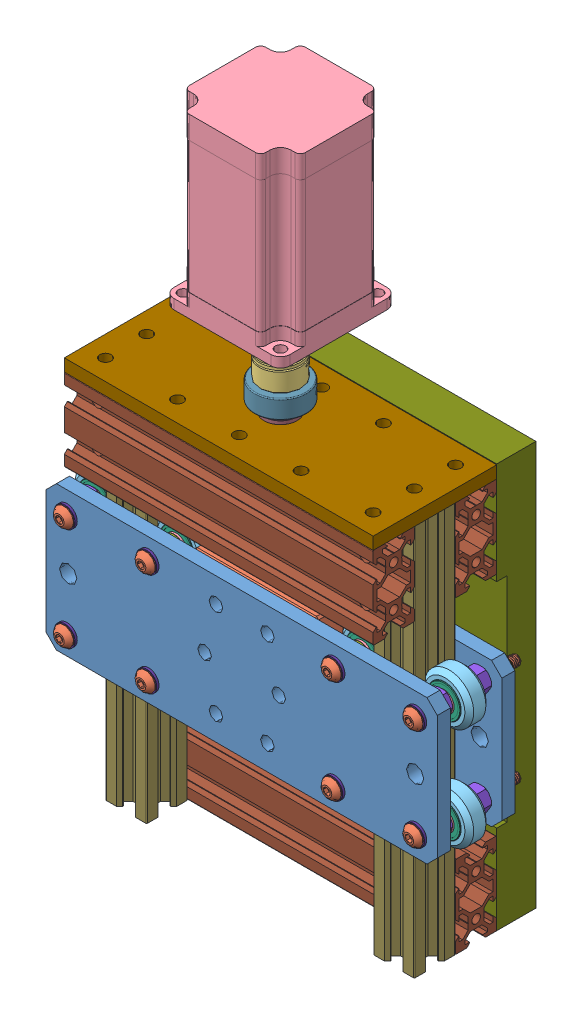
SolidWorks assembly Longitudinal Trim Assembly, configuration Default. Lengths in mm.
Overall size (193.6 327 79.05).
151 component instances, 22 part files, 69 mates.
Components (placement in the parent):
- Trim Sled Assembly-1: Trim Sled Assembly [Default] at origin size (193.6 74.69 37.7)
  - Trim Sled Plate-1: Trim Sled Plate [Default] at origin size (190 70 6.35)
  - Lead Screw Nut Assembly-1: Lead Screw Nut Assembly [Default] at origin size (60 70 25)
    - Lead Screw Nut Clamshell-1: Lead Screw Nut Clamshell [Default] at origin size (60 70 12.5)
    - MISUMI Brass Lead Screw Flange Nut - MTSGR12-1: MISUMI Brass Lead Screw Flange Nut - MTSGR12 [Default] at (0 -15 30) x (0 1 0) z (0 0 1) size (30 44 24)
    - Lead Screw Nut Clamshell-2: Lead Screw Nut Clamshell [Default] at (0 0 60) x (-1 0 0) z (0 0 -1) size (60 70 12.5)
  - Inboard Wheel Stack-1: Inboard Wheel Stack [Default] at (-45.15 -25 23.5) size (23.9 23.9 25)
    - Xtreme Solid V Wheel Kit Assembly-1: Xtreme Solid V Wheel Kit Assembly [Default] at origin size (23.9 23.9 13)
      - Precision Shim - 10x5x1mm-1: Precision Shim - 10x5x1mm [Default] at origin size (10 10 1)
      - Xtreme Solid V Wheel Assembly-1: Xtreme Solid V Wheel Assembly [Default] at (45.15 25 -23.5) size (23.9 23.9 11)
        - Xtreme Solid V Wheel-1: Xtreme Solid V Wheel [Default] at (-45.15 -25 30) x (0 0 1) z (-1 0 0) size (10.2 23.9 23.9)
        - Wheel+Kit+-+5x16x5mm+Sealed+Radial+Ball+Bearing.step.f3d-1: Wheel+Kit+-+5x16x5mm+Sealed+Radial+Ball+Bearing.step.f3d [Default] at (-45.15 -25 30) x (0 1 0) z (-1 0 0) size (16 5 16)
        - Wheel+Kit+-+5x16x5mm+Sealed+Radial+Ball+Bearing.step.f3d-2: Wheel+Kit+-+5x16x5mm+Sealed+Radial+Ball+Bearing.step.f3d [Default] at (-45.15 -25 30) x (0 1 0) z (1 0 0) size (16 5 16)
      - Precision Shim - 10x5x1mm-2: Precision Shim - 10x5x1mm [Default] at (0 0 12) size (10 10 1)
    - Aluminum Spacer 6mm-1: Aluminum Spacer 6mm [Default] at (0 0 -6) size (10 10 6)
    - Aluminum Spacer 6mm-2: Aluminum Spacer 6mm [Default] at (0 0 13) size (10 10 6)
  - Inboard Wheel Stack_1-1: Inboard Wheel Stack_1 [Default] at (-45.15 25 23.5) size (23.9 23.9 25)
    - Xtreme Solid V Wheel Kit Assembly_1-1: Xtreme Solid V Wheel Kit Assembly_1 [Default] at origin size (23.9 23.9 13)
      - Precision Shim - 10x5x1mm-1: Precision Shim - 10x5x1mm [Default] at origin size (10 10 1)
      - Xtreme Solid V Wheel Assembly_1-1: Xtreme Solid V Wheel Assembly_1 [Default] at (45.15 55 -23.5) size (23.9 23.9 11)
        - Xtreme Solid V Wheel-1: Xtreme Solid V Wheel [Default] at (-45.15 -55 30) x (0 0 1) z (-1 0 0) size (10.2 23.9 23.9)
        - Wheel+Kit+-+5x16x5mm+Sealed+Radial+Ball+Bearing.step.f3d-1: Wheel+Kit+-+5x16x5mm+Sealed+Radial+Ball+Bearing.step.f3d [Default] at (-45.15 -55 30) x (0 1 0) z (-1 0 0) size (16 5 16)
        - Wheel+Kit+-+5x16x5mm+Sealed+Radial+Ball+Bearing.step.f3d-2: Wheel+Kit+-+5x16x5mm+Sealed+Radial+Ball+Bearing.step.f3d [Default] at (-45.15 -55 30) x (0 1 0) z (1 0 0) size (16 5 16)
      - Precision Shim - 10x5x1mm-2: Precision Shim - 10x5x1mm [Default] at (0 0 12) size (10 10 1)
    - Aluminum Spacer 6mm-1: Aluminum Spacer 6mm [Default] at (0 0 -6) size (10 10 6)
    - Aluminum Spacer 6mm-2: Aluminum Spacer 6mm [Default] at (0 0 13) size (10 10 6)
  - Inboard Wheel Stack_2-1: Inboard Wheel Stack_2 [Default] at (45.15 25 23.5) size (23.9 23.9 25)
    - Xtreme Solid V Wheel Kit Assembly_2-1: Xtreme Solid V Wheel Kit Assembly_2 [Default] at origin size (23.9 23.9 13)
      - Precision Shim - 10x5x1mm-1: Precision Shim - 10x5x1mm [Default] at origin size (10 10 1)
      - Xtreme Solid V Wheel Assembly_2-1: Xtreme Solid V Wheel Assembly_2 [Default] at (154.85 55 -23.5) size (23.9 23.9 11)
        - Xtreme Solid V Wheel-1: Xtreme Solid V Wheel [Default] at (-154.85 -55 30) x (0 0 1) z (-1 0 0) size (10.2 23.9 23.9)
        - Wheel+Kit+-+5x16x5mm+Sealed+Radial+Ball+Bearing.step.f3d-1: Wheel+Kit+-+5x16x5mm+Sealed+Radial+Ball+Bearing.step.f3d [Default] at (-154.85 -55 30) x (0 1 0) z (-1 0 0) size (16 5 16)
        - Wheel+Kit+-+5x16x5mm+Sealed+Radial+Ball+Bearing.step.f3d-2: Wheel+Kit+-+5x16x5mm+Sealed+Radial+Ball+Bearing.step.f3d [Default] at (-154.85 -55 30) x (0 1 0) z (1 0 0) size (16 5 16)
      - Precision Shim - 10x5x1mm-2: Precision Shim - 10x5x1mm [Default] at (0 0 12) size (10 10 1)
    - Aluminum Spacer 6mm-1: Aluminum Spacer 6mm [Default] at (0 0 -6) size (10 10 6)
    - Aluminum Spacer 6mm-2: Aluminum Spacer 6mm [Default] at (0 0 13) size (10 10 6)
  - Inboard Wheel Stack_3-1: Inboard Wheel Stack_3 [Default] at (45.15 -25 23.5) size (23.9 23.9 25)
    - Xtreme Solid V Wheel Kit Assembly_3-1: Xtreme Solid V Wheel Kit Assembly_3 [Default] at origin size (23.9 23.9 13)
      - Precision Shim - 10x5x1mm-1: Precision Shim - 10x5x1mm [Default] at origin size (10 10 1)
      - Xtreme Solid V Wheel Assembly_3-1: Xtreme Solid V Wheel Assembly_3 [Default] at (154.85 25 -23.5) size (23.9 23.9 11)
        - Xtreme Solid V Wheel-1: Xtreme Solid V Wheel [Default] at (-154.85 -25 30) x (0 0 1) z (-1 0 0) size (10.2 23.9 23.9)
        - Wheel+Kit+-+5x16x5mm+Sealed+Radial+Ball+Bearing.step.f3d-1: Wheel+Kit+-+5x16x5mm+Sealed+Radial+Ball+Bearing.step.f3d [Default] at (-154.85 -25 30) x (0 1 0) z (-1 0 0) size (16 5 16)
        - Wheel+Kit+-+5x16x5mm+Sealed+Radial+Ball+Bearing.step.f3d-2: Wheel+Kit+-+5x16x5mm+Sealed+Radial+Ball+Bearing.step.f3d [Default] at (-154.85 -25 30) x (0 1 0) z (1 0 0) size (16 5 16)
      - Precision Shim - 10x5x1mm-2: Precision Shim - 10x5x1mm [Default] at (0 0 12) size (10 10 1)
    - Aluminum Spacer 6mm-1: Aluminum Spacer 6mm [Default] at (0 0 -6) size (10 10 6)
    - Aluminum Spacer 6mm-2: Aluminum Spacer 6mm [Default] at (0 0 13) size (10 10 6)
  - Outboard Wheel Stack-1: Outboard Wheel Stack [Default] at (-84.85 -25.79 23.5) size (23.9 23.9 30)
    - Xtreme Solid V Wheel Kit Assembly_4-1: Xtreme Solid V Wheel Kit Assembly_4 [Default] at origin size (23.9 23.9 13)
      - Precision Shim - 10x5x1mm-1: Precision Shim - 10x5x1mm [Default] at origin size (10 10 1)
      - Xtreme Solid V Wheel Assembly_4-1: Xtreme Solid V Wheel Assembly_4 [Default] at (84.85 25.79 -23.5) size (23.9 23.9 11)
        - Xtreme Solid V Wheel-1: Xtreme Solid V Wheel [Default] at (-84.85 -25.79 30) x (0 0 1) z (-1 0 0) size (10.2 23.9 23.9)
        - Wheel+Kit+-+5x16x5mm+Sealed+Radial+Ball+Bearing.step.f3d-1: Wheel+Kit+-+5x16x5mm+Sealed+Radial+Ball+Bearing.step.f3d [Default] at (-84.85 -25.79 30) x (0 1 0) z (-1 0 0) size (16 5 16)
        - Wheel+Kit+-+5x16x5mm+Sealed+Radial+Ball+Bearing.step.f3d-2: Wheel+Kit+-+5x16x5mm+Sealed+Radial+Ball+Bearing.step.f3d [Default] at (-84.85 -25.79 30) x (0 1 0) z (1 0 0) size (16 5 16)
      - Precision Shim - 10x5x1mm-2: Precision Shim - 10x5x1mm [Default] at (0 0 12) size (10 10 1)
    - Eccentric Spacer 6mm-1: Eccentric Spacer 6mm [Default] at (0 0.79 -6) x (1 0 0) z (0 -1 0) size (11.55 8.5 10)
    - Eccentric Spacer 6mm-2: Eccentric Spacer 6mm [Default] at (0 0.79 19) x (-1 0 0) z (0 -1 0) size (11.55 8.5 10)
  - Outboard Wheel Stack_1-1: Outboard Wheel Stack_1 [Default] at (-84.85 24.21 23.5) size (23.9 23.9 30)
    - Xtreme Solid V Wheel Kit Assembly_5-1: Xtreme Solid V Wheel Kit Assembly_5 [Default] at origin size (23.9 23.9 13)
      - Precision Shim - 10x5x1mm-1: Precision Shim - 10x5x1mm [Default] at origin size (10 10 1)
      - Xtreme Solid V Wheel Assembly_5-1: Xtreme Solid V Wheel Assembly_5 [Default] at (84.85 55.79 -23.5) size (23.9 23.9 11)
        - Xtreme Solid V Wheel-1: Xtreme Solid V Wheel [Default] at (-84.85 -55.79 30) x (0 0 1) z (-1 0 0) size (10.2 23.9 23.9)
        - Wheel+Kit+-+5x16x5mm+Sealed+Radial+Ball+Bearing.step.f3d-1: Wheel+Kit+-+5x16x5mm+Sealed+Radial+Ball+Bearing.step.f3d [Default] at (-84.85 -55.79 30) x (0 1 0) z (-1 0 0) size (16 5 16)
        - Wheel+Kit+-+5x16x5mm+Sealed+Radial+Ball+Bearing.step.f3d-2: Wheel+Kit+-+5x16x5mm+Sealed+Radial+Ball+Bearing.step.f3d [Default] at (-84.85 -55.79 30) x (0 1 0) z (1 0 0) size (16 5 16)
      - Precision Shim - 10x5x1mm-2: Precision Shim - 10x5x1mm [Default] at (0 0 12) size (10 10 1)
    - Eccentric Spacer 6mm-1: Eccentric Spacer 6mm [Default] at (0 0.79 -6) x (1 0 0) z (0 -1 0) size (11.55 8.5 10)
    - Eccentric Spacer 6mm-2: Eccentric Spacer 6mm [Default] at (0 0.79 19) x (-1 0 0) z (0 -1 0) size (11.55 8.5 10)
  - Outboard Wheel Stack_2-1: Outboard Wheel Stack_2 [Default] at (84.85 24.21 23.5) size (23.9 23.9 30)
    - Xtreme Solid V Wheel Kit Assembly_6-1: Xtreme Solid V Wheel Kit Assembly_6 [Default] at origin size (23.9 23.9 13)
      - Precision Shim - 10x5x1mm-1: Precision Shim - 10x5x1mm [Default] at origin size (10 10 1)
      - Xtreme Solid V Wheel Assembly_6-1: Xtreme Solid V Wheel Assembly_6 [Default] at (115.15 55.79 -23.5) size (23.9 23.9 11)
        - Xtreme Solid V Wheel-1: Xtreme Solid V Wheel [Default] at (-115.15 -55.79 30) x (0 0 1) z (-1 0 0) size (10.2 23.9 23.9)
        - Wheel+Kit+-+5x16x5mm+Sealed+Radial+Ball+Bearing.step.f3d-1: Wheel+Kit+-+5x16x5mm+Sealed+Radial+Ball+Bearing.step.f3d [Default] at (-115.15 -55.79 30) x (0 1 0) z (-1 0 0) size (16 5 16)
        - Wheel+Kit+-+5x16x5mm+Sealed+Radial+Ball+Bearing.step.f3d-2: Wheel+Kit+-+5x16x5mm+Sealed+Radial+Ball+Bearing.step.f3d [Default] at (-115.15 -55.79 30) x (0 1 0) z (1 0 0) size (16 5 16)
      - Precision Shim - 10x5x1mm-2: Precision Shim - 10x5x1mm [Default] at (0 0 12) size (10 10 1)
    - Eccentric Spacer 6mm-1: Eccentric Spacer 6mm [Default] at (0 0.79 -6) x (1 0 0) z (0 -1 0) size (11.55 8.5 10)
    - Eccentric Spacer 6mm-2: Eccentric Spacer 6mm [Default] at (0 0.79 19) x (-1 0 0) z (0 -1 0) size (11.55 8.5 10)
  - Outboard Wheel Stack_3-1: Outboard Wheel Stack_3 [Default] at (84.85 -25.79 23.5) size (23.9 23.9 30)
    - Xtreme Solid V Wheel Kit Assembly_7-1: Xtreme Solid V Wheel Kit Assembly_7 [Default] at origin size (23.9 23.9 13)
      - Precision Shim - 10x5x1mm-1: Precision Shim - 10x5x1mm [Default] at origin size (10 10 1)
      - Xtreme Solid V Wheel Assembly_7-1: Xtreme Solid V Wheel Assembly_7 [Default] at (115.15 25.79 -23.5) size (23.9 23.9 11)
        - Xtreme Solid V Wheel-1: Xtreme Solid V Wheel [Default] at (-115.15 -25.79 30) x (0 0 1) z (-1 0 0) size (10.2 23.9 23.9)
        - Wheel+Kit+-+5x16x5mm+Sealed+Radial+Ball+Bearing.step.f3d-1: Wheel+Kit+-+5x16x5mm+Sealed+Radial+Ball+Bearing.step.f3d [Default] at (-115.15 -25.79 30) x (0 1 0) z (-1 0 0) size (16 5 16)
        - Wheel+Kit+-+5x16x5mm+Sealed+Radial+Ball+Bearing.step.f3d-2: Wheel+Kit+-+5x16x5mm+Sealed+Radial+Ball+Bearing.step.f3d [Default] at (-115.15 -25.79 30) x (0 1 0) z (1 0 0) size (16 5 16)
      - Precision Shim - 10x5x1mm-2: Precision Shim - 10x5x1mm [Default] at (0 0 12) size (10 10 1)
    - Eccentric Spacer 6mm-1: Eccentric Spacer 6mm [Default] at (0 0.79 -6) x (1 0 0) z (0 -1 0) size (11.55 8.5 10)
    - Eccentric Spacer 6mm-2: Eccentric Spacer 6mm [Default] at (0 0.79 19) x (-1 0 0) z (0 -1 0) size (11.55 8.5 10)
  - Trim Sled Plate-2: Trim Sled Plate [Default] at (0 0 31.35) size (190 70 6.35)
- Rear Plate Assembly-1: Rear Plate Assembly [Default] at origin size (150 6 60)
  - Rear Plate-1: Rear Plate [Default] at origin size (150 6 60)
  - 6658K734-1: 6658K734 [Default] at (0 98 30) x (1 0 0) z (0 -1 0) size (12.03 12.03 6)
- Aft Frame Assembly-1: Aft Frame Assembly [Default] at origin size (150 190 60)
  - V-Slot 20x40x150 Linear Rail-1: V-Slot 20x40x150 Linear Rail [Default] at (-75 75 10) x (0 0 -1) z (1 0 0) size (20 40 150)
  - V-Slot 20x20x190 Linear Rail Tapped Ends-1: V-Slot 20x20x190 Linear Rail Tapped Ends [Default] at (65 95 30) x (1 0 0) z (0 -1 0) size (20 20 190)
  - V-Slot 20x20x190 Linear Rail Tapped Ends-2: V-Slot 20x20x190 Linear Rail Tapped Ends [Default] at (-65 95 30) x (1 0 0) z (0 -1 0) size (20 20 190)
  - V-Slot 20x40x150 Linear Rail-2: V-Slot 20x40x150 Linear Rail [Default] at (-75 75 50) x (0 0 -1) z (1 0 0) size (20 40 150)
- V-Slot 20x40x150 Linear Rail-1: V-Slot 20x40x150 Linear Rail [Default] at (-75 -75 10) x (0 0 -1) z (1 0 0) size (20 40 150)
- 7806K630-1: 7806K630 [Default] at (0 92.5 30) size (16 5.01 16)
- 7806K630-2: 7806K630 [Default] at (0 103.5 30) size (16 5.01 16)
- 57445K24 - 8mm Clamping Shaft Collar-1: 57445K24 - 8mm Clamping Shaft Collar [Default] at (0 110.5 30) x (1 0 0) z (0 1 0) size (25 25.02 9.05)
- MTSBRA12-160-S35-Q8-1: MTSBRA12-160-S35-Q8 [Default] at (0 125 30) x (1 0 0) z (0 -1 0) size (11.91 11.91 160)
- Trim Riser Board-1: Trim Riser Board [Default] at origin size (150 196.35 19.05)
- 93475A240-1: 93475A240 [Default] at (84.85 -25 48.85) x (0.893587 -0.448891 0) z (0 0 1) size (10 10 1.1)
- 93475A240-2: 93475A240 [Default] at (84.85 -25 10.05) x (0.893587 -0.448891 0) z (0 0 1) size (10 10 1.1)
- 93625A200 - M5 x 0.8 mm Nylon-Insert Locknut-1: 93625A200 - M5 x 0.8 mm Nylon-Insert Locknut [Default] at (84.85 -25 10.05) x (1 0 0) z (0 0 -1) size (8 9.24 5)
  - 93625A200 - M5 x 0.8 mm Nylon-Insert Locknut_2-1: 93625A200 - M5 x 0.8 mm Nylon-Insert Locknut_2 [Default] at origin size (8 9.24 5)
  - 93625A200 - M5 x 0.8 mm Nylon-Insert Locknut-1: 93625A200 - M5 x 0.8 mm Nylon-Insert Locknut [Default] at origin size (7.53 7.53 0.53)
- 92095A228 - BHCS, M5-0.8 X 50, 18-8-1: 92095A228 - BHCS, M5-0.8 X 50, 18-8 [92095A228] at (84.85 -25 52.7) x (-0.790957 0.611872 0) z (0 0 1) size (9.5 9.5 53.02)
- 93475A240-3: 93475A240 [Default] at (45.15 -25 48.85) x (0.953456 -0.301532 0) z (0 0 1) size (10 10 1.1)
- 93475A240-4: 93475A240 [Default] at (45.15 -25 10.05) x (0.953456 -0.301532 0) z (0 0 1) size (10 10 1.1)
- 93625A200 - M5 x 0.8 mm Nylon-Insert Locknut-2: 93625A200 - M5 x 0.8 mm Nylon-Insert Locknut [Default] at (45.15 -25 10.05) x (0.987351 0.158553 0) z (0 0 -1) size (8 9.24 5)
  - 93625A200 - M5 x 0.8 mm Nylon-Insert Locknut_2-1: 93625A200 - M5 x 0.8 mm Nylon-Insert Locknut_2 [Default] at origin size (8 9.24 5)
  - 93625A200 - M5 x 0.8 mm Nylon-Insert Locknut-1: 93625A200 - M5 x 0.8 mm Nylon-Insert Locknut [Default] at origin size (7.53 7.53 0.53)
- 92095A228 - BHCS, M5-0.8 X 50, 18-8-2: 92095A228 - BHCS, M5-0.8 X 50, 18-8 [92095A228] at (45.15 -25 52.7) x (-0.877966 0.478723 0) z (0 0 1) size (9.5 9.5 53.02)
- 93475A240-5: 93475A240 [Default] at (84.85 24.21 48.85) x (0.98409 -0.177672 0) z (0 0 1) size (10 10 1.1)
- 93475A240-6: 93475A240 [Default] at (84.85 24.21 10.05) x (0.98409 -0.177672 0) z (0 0 1) size (10 10 1.1)
- 93625A200 - M5 x 0.8 mm Nylon-Insert Locknut-3: 93625A200 - M5 x 0.8 mm Nylon-Insert Locknut [Default] at (84.85 24.21 10.05) x (0.959125 0.282984 0) z (0 0 -1) size (8 9.24 5)
  - 93625A200 - M5 x 0.8 mm Nylon-Insert Locknut_2-1: 93625A200 - M5 x 0.8 mm Nylon-Insert Locknut_2 [Default] at origin size (8 9.24 5)
  - 93625A200 - M5 x 0.8 mm Nylon-Insert Locknut-1: 93625A200 - M5 x 0.8 mm Nylon-Insert Locknut [Default] at origin size (7.53 7.53 0.53)
- 92095A228 - BHCS, M5-0.8 X 50, 18-8-3: 92095A228 - BHCS, M5-0.8 X 50, 18-8 [92095A228] at (84.85 24.21 52.7) x (-0.931776 0.363033 0) z (0 0 1) size (9.5 9.5 53.02)
- 93475A240-7: 93475A240 [Default] at (45.15 25 48.85) x (0.996366 -0.085169 0) z (0 0 1) size (10 10 1.1)
- 93475A240-8: 93475A240 [Default] at (45.15 25 10.05) x (0.996366 -0.085169 0) z (0 0 1) size (10 10 1.1)
- 93625A200 - M5 x 0.8 mm Nylon-Insert Locknut-4: 93625A200 - M5 x 0.8 mm Nylon-Insert Locknut [Default] at (45.15 25 10.05) x (0.928571 0.371154 0) z (0 0 -1) size (8 9.24 5)
  - 93625A200 - M5 x 0.8 mm Nylon-Insert Locknut_2-1: 93625A200 - M5 x 0.8 mm Nylon-Insert Locknut_2 [Default] at origin size (8 9.24 5)
  - 93625A200 - M5 x 0.8 mm Nylon-Insert Locknut-1: 93625A200 - M5 x 0.8 mm Nylon-Insert Locknut [Default] at origin size (7.53 7.53 0.53)
- 92095A228 - BHCS, M5-0.8 X 50, 18-8-4: 92095A228 - BHCS, M5-0.8 X 50, 18-8 [92095A228] at (45.15 25 52.7) x (-0.961559 0.2746 0) z (0 0 1) size (9.5 9.5 53.02)
- 93475A240-9: 93475A240 [Default] at (-45.15 -25 48.85) x (0.999525 -0.030802 0) z (0 0 1) size (10 10 1.1)
- 93475A240-10: 93475A240 [Default] at (-45.15 -25 10.05) x (0.999525 -0.030802 0) z (0 0 1) size (10 10 1.1)
- 93625A200 - M5 x 0.8 mm Nylon-Insert Locknut-5: 93625A200 - M5 x 0.8 mm Nylon-Insert Locknut [Default] at (-45.15 -25 10.05) x (0.906989 0.421154 0) z (0 0 -1) size (8 9.24 5)
  - 93625A200 - M5 x 0.8 mm Nylon-Insert Locknut_2-1: 93625A200 - M5 x 0.8 mm Nylon-Insert Locknut_2 [Default] at origin size (8 9.24 5)
  - 93625A200 - M5 x 0.8 mm Nylon-Insert Locknut-1: 93625A200 - M5 x 0.8 mm Nylon-Insert Locknut [Default] at origin size (7.53 7.53 0.53)
- 92095A228 - BHCS, M5-0.8 X 50, 18-8-5: 92095A228 - BHCS, M5-0.8 X 50, 18-8 [92095A228] at (-45.15 -25 52.7) x (-0.975082 0.221847 0) z (0 0 1) size (9.5 9.5 53.02)
- 93475A240-11: 93475A240 [Default] at (-84.85 -25.79 48.85) x (0.999778 -0.021077 0) z (0 0 1) size (10 10 1.1)
- 93475A240-12: 93475A240 [Default] at (-84.85 -25.79 10.05) x (0.999778 -0.021077 0) z (0 0 1) size (10 10 1.1)
- 93625A200 - M5 x 0.8 mm Nylon-Insert Locknut-6: 93625A200 - M5 x 0.8 mm Nylon-Insert Locknut [Default] at (-84.85 -25.79 10.05) x (0.902849 0.429957 0) z (0 0 -1) size (8 9.24 5)
  - 93625A200 - M5 x 0.8 mm Nylon-Insert Locknut_2-1: 93625A200 - M5 x 0.8 mm Nylon-Insert Locknut_2 [Default] at origin size (8 9.24 5)
  - 93625A200 - M5 x 0.8 mm Nylon-Insert Locknut-1: 93625A200 - M5 x 0.8 mm Nylon-Insert Locknut [Default] at origin size (7.53 7.53 0.53)
- 92095A228 - BHCS, M5-0.8 X 50, 18-8-6: 92095A228 - BHCS, M5-0.8 X 50, 18-8 [92095A228] at (-84.85 -25.79 52.7) x (-0.977194 0.212351 0) z (0 0 1) size (9.5 9.5 53.02)
- 93475A240-13: 93475A240 [Default] at (-45.15 25 48.85) x (0.998089 -0.061788 0) z (0 0 1) size (10 10 1.1)
- 93475A240-14: 93475A240 [Default] at (-45.15 25 10.05) x (0.998089 -0.061788 0) z (0 0 1) size (10 10 1.1)
- 93625A200 - M5 x 0.8 mm Nylon-Insert Locknut-7: 93625A200 - M5 x 0.8 mm Nylon-Insert Locknut [Default] at (-45.15 25 10.05) x (0.919615 0.39282 0) z (0 0 -1) size (8 9.24 5)
  - 93625A200 - M5 x 0.8 mm Nylon-Insert Locknut_2-1: 93625A200 - M5 x 0.8 mm Nylon-Insert Locknut_2 [Default] at origin size (8 9.24 5)
  - 93625A200 - M5 x 0.8 mm Nylon-Insert Locknut-1: 93625A200 - M5 x 0.8 mm Nylon-Insert Locknut [Default] at origin size (7.53 7.53 0.53)
- 92095A228 - BHCS, M5-0.8 X 50, 18-8-7: 92095A228 - BHCS, M5-0.8 X 50, 18-8 [92095A228] at (-45.15 25 52.7) x (-0.967732 0.251983 0) z (0 0 1) size (9.5 9.5 53.02)
- 93475A240-15: 93475A240 [Default] at (-84.85 24.21 48.85) x (0.987935 -0.154868 0) z (0 0 1) size (10 10 1.1)
- 93475A240-16: 93475A240 [Default] at (-84.85 24.21 10.05) x (0.987935 -0.154868 0) z (0 0 1) size (10 10 1.1)
- 93625A200 - M5 x 0.8 mm Nylon-Insert Locknut-8: 93625A200 - M5 x 0.8 mm Nylon-Insert Locknut [Default] at (-84.85 24.21 10.05) x (0.952324 0.305088 0) z (0 0 -1) size (8 9.24 5)
  - 93625A200 - M5 x 0.8 mm Nylon-Insert Locknut_2-1: 93625A200 - M5 x 0.8 mm Nylon-Insert Locknut_2 [Default] at origin size (8 9.24 5)
  - 93625A200 - M5 x 0.8 mm Nylon-Insert Locknut-1: 93625A200 - M5 x 0.8 mm Nylon-Insert Locknut [Default] at origin size (7.53 7.53 0.53)
- 92095A228 - BHCS, M5-0.8 X 50, 18-8-8: 92095A228 - BHCS, M5-0.8 X 50, 18-8 [92095A228] at (-84.85 24.21 52.7) x (-0.939922 0.341389 0) z (0 0 1) size (9.5 9.5 53.02)
- 819368020915 - Flexible Coupling 5mm x 0.25in-1: 819368020915 - Flexible Coupling 5mm x 0.25in [Default] at (0 115.4 30) x (-0.294074 0 -0.955783) z (0 -1 0) size (20 20 25)
- 819368021257 - Nema 23 High Torque Stepper Motor-1: 819368021257 - Nema 23 High Torque Stepper Motor [Default] at (0 146 30) x (1 0 0) z (0 -1 0) size (56.4 56.4 106.6)
Mates (geometry in assembly coordinates):
- Concentric20: concentric anti-aligned: cylinder of Trim Sled Assembly-1/Trim Sled Plate-2 through (84.85 -25 45.3575) axis (0 0 -1) radius 3.5; cylinder of 93475A240-1 through (84.85 -25 48.85) axis (0 0 1) radius 5
- Coincident23: coincident anti-aligned: plane of Trim Sled Assembly-1/Trim Sled Plate-2 through (0 0 48.85) normal (0 0 1); plane of 93475A240-1 through (84.85 -25 48.85) normal (0 0 -1)
- Concentric22: concentric aligned: cylinder of 93475A240-1 through (84.85 -25 48.85) axis (0 0 1) radius 5; cylinder of 93475A240-2 through (84.85 -25 10.05) axis (0 0 1) radius 5
- Concentric24: concentric aligned: cylinder of 93475A240-1 through (84.85 -25 48.85) axis (0 0 1) radius 5; cylinder of 92095A228 - BHCS, M5-0.8 X 50, 18-8-1 through (84.85 -25 52.7) axis (0 0 1) radius 4.75
- Coincident26: coincident anti-aligned: plane of 93475A240-1 through (84.85 -25 49.95) normal (0 0 1); plane of 92095A228 - BHCS, M5-0.8 X 50, 18-8-1 through (87.7564 -21.243 49.95) normal (0 0 -1)
- Coincident24: coincident anti-aligned: plane of Trim Sled Assembly-1/Trim Sled Plate-1 through (0 0 11.15) normal (0 0 -1); plane of 93475A240-2 through (84.85 -25 11.15) normal (0 0 1)
- Coincident25: coincident anti-aligned: plane of 93475A240-2 through (84.85 -25 10.05) normal (0 0 -1); plane of 93625A200 - M5 x 0.8 mm Nylon-Insert Locknut-1/93625A200 - M5 x 0.8 mm Nylon-Insert Locknut_2-1 through (84.85 -29.6188 10.05) normal (0 0 1)
- Concentric23: concentric aligned: cylinder of 93475A240-2 through (84.85 -25 10.05) axis (0 0 1) radius 5; cylinder of 93625A200 - M5 x 0.8 mm Nylon-Insert Locknut-1/93625A200 - M5 x 0.8 mm Nylon-Insert Locknut-1 through (84.85 -25 5.8071) axis (0 0 1) radius 2.1277
- Concentric25: concentric aligned: cylinder of 93475A240-3 through (45.15 -25 48.85) axis (0 0 1) radius 5; cylinder of 93475A240-4 through (45.15 -25 10.05) axis (0 0 1) radius 5
- Concentric26: concentric aligned: cylinder of 93475A240-3 through (45.15 -25 48.85) axis (0 0 1) radius 5; cylinder of 92095A228 - BHCS, M5-0.8 X 50, 18-8-2 through (45.15 -25 52.7) axis (0 0 1) radius 4.75
- Coincident27: coincident anti-aligned: plane of 93475A240-3 through (45.15 -25 49.95) normal (0 0 1); plane of 92095A228 - BHCS, M5-0.8 X 50, 18-8-2 through (47.4239 -20.8297 49.95) normal (0 0 -1)
- Coincident28: coincident anti-aligned: plane of 93475A240-4 through (45.15 -25 10.05) normal (0 0 -1); plane of 93625A200 - M5 x 0.8 mm Nylon-Insert Locknut-2/93625A200 - M5 x 0.8 mm Nylon-Insert Locknut_2-1 through (45.8823 -29.5604 10.05) normal (0 0 1)
- Concentric27: concentric aligned: cylinder of 93475A240-4 through (45.15 -25 10.05) axis (0 0 1) radius 5; cylinder of 93625A200 - M5 x 0.8 mm Nylon-Insert Locknut-2/93625A200 - M5 x 0.8 mm Nylon-Insert Locknut-1 through (45.15 -25 5.8071) axis (0 0 1) radius 2.1277
- Coincident29: coincident anti-aligned: plane of Trim Sled Assembly-1/Trim Sled Plate-2 through (0 0 48.85) normal (0 0 1); plane of 93475A240-3 through (45.15 -25 48.85) normal (0 0 -1)
- Coincident30: coincident anti-aligned: plane of Trim Sled Assembly-1/Trim Sled Plate-1 through (0 0 11.15) normal (0 0 -1); plane of 93475A240-4 through (45.15 -25 11.15) normal (0 0 1)
- Concentric28: concentric anti-aligned: cylinder of Trim Sled Assembly-1/Trim Sled Plate-2 through (45.15 -25 45.3575) axis (0 0 -1) radius 2.65; cylinder of 93475A240-3 through (45.15 -25 48.85) axis (0 0 1) radius 5
- Concentric29: concentric aligned: cylinder of 93475A240-5 through (84.85 24.21 48.85) axis (0 0 1) radius 5; cylinder of 93475A240-6 through (84.85 24.21 10.05) axis (0 0 1) radius 5
- Concentric30: concentric aligned: cylinder of 93475A240-5 through (84.85 24.21 48.85) axis (0 0 1) radius 5; cylinder of 92095A228 - BHCS, M5-0.8 X 50, 18-8-3 through (84.85 24.21 52.7) axis (0 0 1) radius 4.75
- Coincident31: coincident anti-aligned: plane of 93475A240-5 through (84.85 24.21 49.95) normal (0 0 1); plane of 92095A228 - BHCS, M5-0.8 X 50, 18-8-3 through (86.5744 28.6359 49.95) normal (0 0 -1)
- Coincident32: coincident anti-aligned: plane of 93475A240-6 through (84.85 24.21 10.05) normal (0 0 -1); plane of 93625A200 - M5 x 0.8 mm Nylon-Insert Locknut-3/93625A200 - M5 x 0.8 mm Nylon-Insert Locknut_2-1 through (86.157 19.78 10.05) normal (0 0 1)
- Concentric31: concentric aligned: cylinder of 93475A240-6 through (84.85 24.21 10.05) axis (0 0 1) radius 5; cylinder of 93625A200 - M5 x 0.8 mm Nylon-Insert Locknut-3/93625A200 - M5 x 0.8 mm Nylon-Insert Locknut-1 through (84.85 24.21 5.8071) axis (0 0 1) radius 2.1277
- Coincident33: coincident anti-aligned: plane of Trim Sled Assembly-1/Trim Sled Plate-2 through (0 0 48.85) normal (0 0 1); plane of 93475A240-5 through (84.85 24.21 48.85) normal (0 0 -1)
- Coincident34: coincident anti-aligned: plane of Trim Sled Assembly-1/Trim Sled Plate-1 through (0 0 11.15) normal (0 0 -1); plane of 93475A240-6 through (84.85 24.21 11.15) normal (0 0 1)
- Concentric32: concentric anti-aligned: cylinder of Trim Sled Assembly-1/Outboard Wheel Stack_2-1/Eccentric Spacer 6mm-2 through (84.85 24.21 45) axis (0 0 -1) radius 2.5; cylinder of 93475A240-5 through (84.85 24.21 48.85) axis (0 0 1) radius 5
- Concentric33: concentric aligned: cylinder of 93475A240-7 through (45.15 25 48.85) axis (0 0 1) radius 5; cylinder of 93475A240-8 through (45.15 25 10.05) axis (0 0 1) radius 5
- Concentric34: concentric aligned: cylinder of 93475A240-7 through (45.15 25 48.85) axis (0 0 1) radius 5; cylinder of 92095A228 - BHCS, M5-0.8 X 50, 18-8-4 through (45.15 25 52.7) axis (0 0 1) radius 4.75
- Coincident35: coincident anti-aligned: plane of 93475A240-7 through (45.15 25 49.95) normal (0 0 1); plane of 92095A228 - BHCS, M5-0.8 X 50, 18-8-4 through (46.4543 29.5674 49.95) normal (0 0 -1)
- Coincident36: coincident anti-aligned: plane of 93475A240-8 through (45.15 25 10.05) normal (0 0 -1); plane of 93625A200 - M5 x 0.8 mm Nylon-Insert Locknut-4/93625A200 - M5 x 0.8 mm Nylon-Insert Locknut_2-1 through (46.8643 20.7111 10.05) normal (0 0 1)
- Concentric35: concentric aligned: cylinder of 93475A240-8 through (45.15 25 10.05) axis (0 0 1) radius 5; cylinder of 93625A200 - M5 x 0.8 mm Nylon-Insert Locknut-4/93625A200 - M5 x 0.8 mm Nylon-Insert Locknut-1 through (45.15 25 5.8071) axis (0 0 1) radius 2.1277
- Coincident37: coincident anti-aligned: plane of Trim Sled Assembly-1/Trim Sled Plate-2 through (0 0 48.85) normal (0 0 1); plane of 93475A240-7 through (45.15 25 48.85) normal (0 0 -1)
- Coincident38: coincident anti-aligned: plane of Trim Sled Assembly-1/Trim Sled Plate-1 through (0 0 11.15) normal (0 0 -1); plane of 93475A240-8 through (45.15 25 11.15) normal (0 0 1)
- Concentric36: concentric anti-aligned: cylinder of Trim Sled Assembly-1/Trim Sled Plate-2 through (45.15 25 45.3575) axis (0 0 -1) radius 2.65; cylinder of 93475A240-7 through (45.15 25 48.85) axis (0 0 1) radius 5
- Concentric37: concentric aligned: cylinder of 93475A240-9 through (-45.15 -25 48.85) axis (0 0 1) radius 5; cylinder of 93475A240-10 through (-45.15 -25 10.05) axis (0 0 1) radius 5
- Concentric38: concentric aligned: cylinder of 93475A240-9 through (-45.15 -25 48.85) axis (0 0 1) radius 5; cylinder of 92095A228 - BHCS, M5-0.8 X 50, 18-8-5 through (-45.15 -25 52.7) axis (0 0 1) radius 4.75
- Coincident39: coincident anti-aligned: plane of 93475A240-9 through (-45.15 -25 49.95) normal (0 0 1); plane of 92095A228 - BHCS, M5-0.8 X 50, 18-8-5 through (-44.0962 -20.3684 49.95) normal (0 0 -1)
- Coincident40: coincident anti-aligned: plane of 93475A240-10 through (-45.15 -25 10.05) normal (0 0 -1); plane of 93625A200 - M5 x 0.8 mm Nylon-Insert Locknut-5/93625A200 - M5 x 0.8 mm Nylon-Insert Locknut_2-1 through (-43.2048 -29.1892 10.05) normal (0 0 1)
- Concentric39: concentric aligned: cylinder of 93475A240-10 through (-45.15 -25 10.05) axis (0 0 1) radius 5; cylinder of 93625A200 - M5 x 0.8 mm Nylon-Insert Locknut-5/93625A200 - M5 x 0.8 mm Nylon-Insert Locknut-1 through (-45.15 -25 5.8071) axis (0 0 1) radius 2.1277
- Coincident41: coincident anti-aligned: plane of Trim Sled Assembly-1/Trim Sled Plate-2 through (0 0 48.85) normal (0 0 1); plane of 93475A240-9 through (-45.15 -25 48.85) normal (0 0 -1)
- Coincident42: coincident anti-aligned: plane of Trim Sled Assembly-1/Trim Sled Plate-1 through (0 0 11.15) normal (0 0 -1); plane of 93475A240-10 through (-45.15 -25 11.15) normal (0 0 1)
- Concentric40: concentric anti-aligned: cylinder of Trim Sled Assembly-1/Trim Sled Plate-2 through (-45.15 -25 45.3575) axis (0 0 -1) radius 2.65; cylinder of 93475A240-9 through (-45.15 -25 48.85) axis (0 0 1) radius 5
- Concentric41: concentric aligned: cylinder of 93475A240-11 through (-84.85 -25.79 48.85) axis (0 0 1) radius 5; cylinder of 93475A240-12 through (-84.85 -25.79 10.05) axis (0 0 1) radius 5
- Concentric42: concentric aligned: cylinder of 93475A240-11 through (-84.85 -25.79 48.85) axis (0 0 1) radius 5; cylinder of 92095A228 - BHCS, M5-0.8 X 50, 18-8-6 through (-84.85 -25.79 52.7) axis (0 0 1) radius 4.75
- Coincident43: coincident anti-aligned: plane of 93475A240-11 through (-84.85 -25.79 49.95) normal (0 0 1); plane of 92095A228 - BHCS, M5-0.8 X 50, 18-8-6 through (-83.8413 -21.1483 49.95) normal (0 0 -1)
- Coincident44: coincident anti-aligned: plane of 93475A240-12 through (-84.85 -25.79 10.05) normal (0 0 -1); plane of 93625A200 - M5 x 0.8 mm Nylon-Insert Locknut-6/93625A200 - M5 x 0.8 mm Nylon-Insert Locknut_2-1 through (-82.8641 -29.9601 10.05) normal (0 0 1)
- Concentric43: concentric aligned: cylinder of 93475A240-12 through (-84.85 -25.79 10.05) axis (0 0 1) radius 5; cylinder of 93625A200 - M5 x 0.8 mm Nylon-Insert Locknut-6/93625A200 - M5 x 0.8 mm Nylon-Insert Locknut-1 through (-84.85 -25.79 5.8071) axis (0 0 1) radius 2.1277
- Coincident45: coincident anti-aligned: plane of Trim Sled Assembly-1/Trim Sled Plate-2 through (0 0 48.85) normal (0 0 1); plane of 93475A240-11 through (-84.85 -25.79 48.85) normal (0 0 -1)
- Coincident46: coincident anti-aligned: plane of Trim Sled Assembly-1/Trim Sled Plate-1 through (0 0 11.15) normal (0 0 -1); plane of 93475A240-12 through (-84.85 -25.79 11.15) normal (0 0 1)
- Concentric44: concentric anti-aligned: cylinder of Trim Sled Assembly-1/Outboard Wheel Stack-1/Eccentric Spacer 6mm-2 through (-84.85 -25.79 45) axis (0 0 -1) radius 2.5; cylinder of 93475A240-11 through (-84.85 -25.79 48.85) axis (0 0 1) radius 5
- Concentric45: concentric aligned: cylinder of 93475A240-13 through (-45.15 25 48.85) axis (0 0 1) radius 5; cylinder of 93475A240-14 through (-45.15 25 10.05) axis (0 0 1) radius 5
- Concentric46: concentric aligned: cylinder of 93475A240-13 through (-45.15 25 48.85) axis (0 0 1) radius 5; cylinder of 92095A228 - BHCS, M5-0.8 X 50, 18-8-7 through (-45.15 25 52.7) axis (0 0 1) radius 4.75
- Coincident47: coincident anti-aligned: plane of 93475A240-13 through (-45.15 25 49.95) normal (0 0 1); plane of 92095A228 - BHCS, M5-0.8 X 50, 18-8-7 through (-43.9531 29.5967 49.95) normal (0 0 -1)
- Coincident48: coincident anti-aligned: plane of 93475A240-14 through (-45.15 25 10.05) normal (0 0 -1); plane of 93625A200 - M5 x 0.8 mm Nylon-Insert Locknut-7/93625A200 - M5 x 0.8 mm Nylon-Insert Locknut_2-1 through (-43.3356 20.7525 10.05) normal (0 0 1)
- Concentric47: concentric aligned: cylinder of 93475A240-14 through (-45.15 25 10.05) axis (0 0 1) radius 5; cylinder of 93625A200 - M5 x 0.8 mm Nylon-Insert Locknut-7/93625A200 - M5 x 0.8 mm Nylon-Insert Locknut-1 through (-45.15 25 5.8071) axis (0 0 1) radius 2.1277
- Coincident49: coincident anti-aligned: plane of Trim Sled Assembly-1/Trim Sled Plate-2 through (0 0 48.85) normal (0 0 1); plane of 93475A240-13 through (-45.15 25 48.85) normal (0 0 -1)
- Coincident50: coincident anti-aligned: plane of Trim Sled Assembly-1/Trim Sled Plate-1 through (0 0 11.15) normal (0 0 -1); plane of 93475A240-14 through (-45.15 25 11.15) normal (0 0 1)
- Concentric48: concentric anti-aligned: cylinder of Trim Sled Assembly-1/Trim Sled Plate-2 through (-45.15 25 45.3575) axis (0 0 -1) radius 2.65; cylinder of 93475A240-13 through (-45.15 25 48.85) axis (0 0 1) radius 5
- Concentric49: concentric aligned: cylinder of 93475A240-15 through (-84.85 24.21 48.85) axis (0 0 1) radius 5; cylinder of 93475A240-16 through (-84.85 24.21 10.05) axis (0 0 1) radius 5
- Concentric50: concentric aligned: cylinder of 93475A240-15 through (-84.85 24.21 48.85) axis (0 0 1) radius 5; cylinder of 92095A228 - BHCS, M5-0.8 X 50, 18-8-8 through (-84.85 24.21 52.7) axis (0 0 1) radius 4.75
- Coincident51: coincident anti-aligned: plane of 93475A240-15 through (-84.85 24.21 49.95) normal (0 0 1); plane of 92095A228 - BHCS, M5-0.8 X 50, 18-8-8 through (-83.2284 28.6746 49.95) normal (0 0 -1)
- Coincident52: coincident anti-aligned: plane of 93475A240-16 through (-84.85 24.21 10.05) normal (0 0 -1); plane of 93625A200 - M5 x 0.8 mm Nylon-Insert Locknut-8/93625A200 - M5 x 0.8 mm Nylon-Insert Locknut_2-1 through (-83.4409 19.8114 10.05) normal (0 0 1)
- Concentric51: concentric aligned: cylinder of 93475A240-16 through (-84.85 24.21 10.05) axis (0 0 1) radius 5; cylinder of 93625A200 - M5 x 0.8 mm Nylon-Insert Locknut-8/93625A200 - M5 x 0.8 mm Nylon-Insert Locknut-1 through (-84.85 24.21 5.8071) axis (0 0 1) radius 2.1277
- Coincident53: coincident anti-aligned: plane of Trim Sled Assembly-1/Trim Sled Plate-2 through (0 0 48.85) normal (0 0 1); plane of 93475A240-15 through (-84.85 24.21 48.85) normal (0 0 -1)
- Coincident54: coincident anti-aligned: plane of Trim Sled Assembly-1/Trim Sled Plate-1 through (0 0 11.15) normal (0 0 -1); plane of 93475A240-16 through (-84.85 24.21 11.15) normal (0 0 1)
- Concentric52: concentric anti-aligned: cylinder of Trim Sled Assembly-1/Outboard Wheel Stack_1-1/Eccentric Spacer 6mm-2 through (-84.85 24.21 45) axis (0 0 -1) radius 2.5; cylinder of 93475A240-15 through (-84.85 24.21 48.85) axis (0 0 1) radius 5
- Concentric56: concentric aligned: cylinder of MTSBRA12-160-S35-Q8-1 through (0 107.5 30) axis (0 -1 0) radius 4; cylinder of 819368020915 - Flexible Coupling 5mm x 0.25in-1 through (0 138.8137 30) axis (0 -1 0) radius 4
- Concentric57: concentric aligned: cylinder of 819368020915 - Flexible Coupling 5mm x 0.25in-1 through (0 127.5 30) axis (0 1 0) radius 3.175; cylinder of 819368021257 - Nema 23 High Torque Stepper Motor-1 through (0 125 30) axis (0 1 0) radius 3.175
- Parallel4: parallel aligned: plane of Rear Plate Assembly-1/Rear Plate-1 through (-75 95 60) normal (0 0 1); plane of 819368021257 - Nema 23 High Torque Stepper Motor-1 through (-23.6 150.4 58.2) normal (0 0 1)
- Coincident61: coincident anti-aligned: plane of 819368020915 - Flexible Coupling 5mm x 0.25in-1 through (0 140 30) normal (0 1 0); plane of 819368021257 - Nema 23 High Torque Stepper Motor-1 through (0 140 30) normal (0 -1 0)
- Distance2: distance = 45 mm anti-aligned: plane of 819368021257 - Nema 23 High Torque Stepper Motor-1 through (-23.6 146 53.6) normal (0 -1 0); plane of Rear Plate Assembly-1/Rear Plate-1 through (0 101 30) normal (0 1 0)
